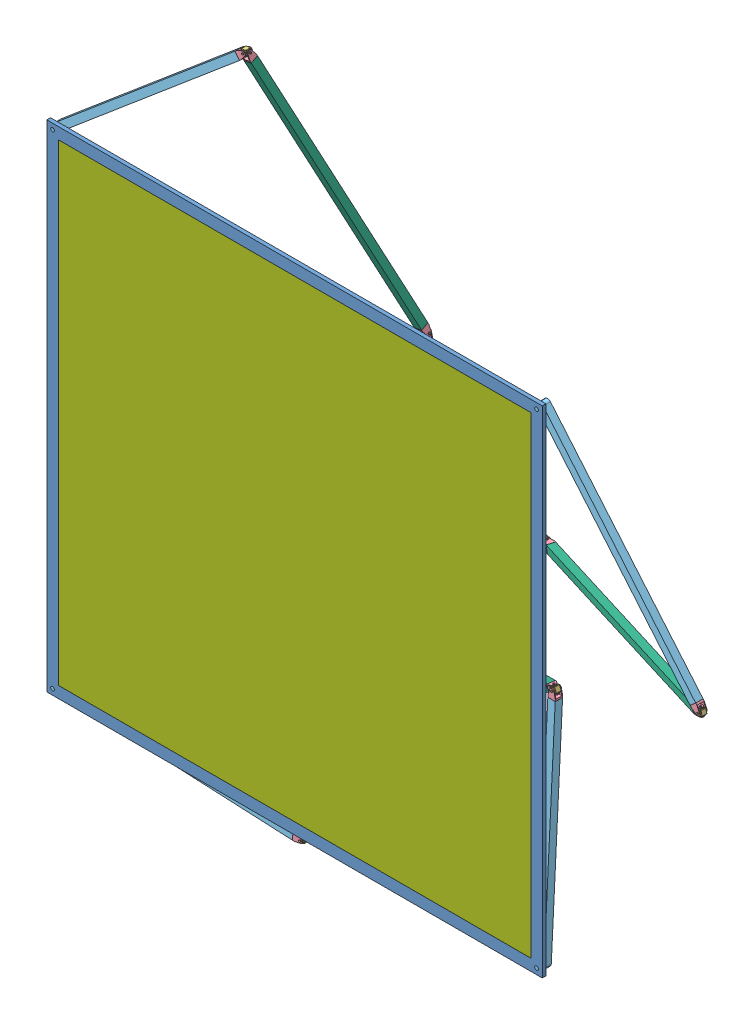
SolidWorks assembly 4ruu_assy, configuration Default. Lengths in mm.
Overall size (1795.63 1894.26 440).
49 component instances, 8 part files, 36 mates.
Components (placement in the parent):
- base_platform-1: base_platform [Default] at origin size (1343.5 1343.5 10)
- moving_platform_v2-1: moving_platform_v2 [Default] at (0 0 -355) x (0.707107 -0.707107 0) z (-0.707107 -0.707107 0) size (455.38 20 455.38)
- leg_assy-13: leg_assy [Default] at (1212.9036 -498.9058 0) x (-0.19613 0.980578 0) z (0.980578 0.19613 0) size (605.2 366.75 808.94) (flexible)
  - U_assy-1: U_assy [Default] at origin size (42.86 32.94 43.11) (flexible)
    - connector_new-2: connector_new [Default] at (661.9873 -10 0) size (23.51 23.51 14.4)
    - U_leg-3: U_leg [Default] at (661.9873 -18.0144 -18.324) x (0 0.916202 -0.400718) z (1 0 0) size (20 35.93 20)
    - U_leg-4: U_leg [Default] at (679.5062 -10 -9.6481) x (-0.482406 0 -0.875948) z (0 1 0) size (20 35.93 20)
  - active_link-2: active_link [Default] at (1241.8535 0 -319.3467) x (-0.875948 0 0.482406) z (-0.482406 0 -0.875948) size (651.99 30 20)
  - passive_link-2: passive_link [Default] at (661.9873 -18.0144 -18.324) x (0 -0.400718 -0.916202) z (0 -0.916202 0.400718) size (796 20 20)
  - U_assy-3: U_assy [Default] at (0 343.3292 -1443.6209) x (1 0 0) z (0 0 -1) size (27.44 32.94 62.87) (flexible)
    - connector_new-2: connector_new [Default] at (661.9873 688.3292 -677.6764) size (23.51 23.51 14.4)
    - U_leg-3: U_leg [Default] at (661.9873 680.3148 -696.0004) x (0 0.916202 -0.400718) z (1 0 0) size (20 35.93 20)
    - U_leg-4: U_leg [Default] at (665.9099 688.3292 -658.0648) x (0.980578 0 -0.19613) z (0 1 0) size (20 35.93 20)
- leg_assy-14: leg_assy [Default] at (360.6975 1504.003 0) x (-0.7718 -0.635865 0) z (-0.635865 0.7718 0) size (685.82 385.73 722.67) (flexible)
  - U_assy-1: U_assy [Default] at origin size (43.88 32.94 45.52) (flexible)
    - connector_new-2: connector_new [Default] at (661.9873 -10 0) x (-0.881522 0 -0.472143) z (0.472143 0 -0.881522) size (23.51 23.51 14.4)
    - U_leg-3: U_leg [Default] at (670.6388 -18.0144 -16.153) x (-0.189196 -0.916202 0.353242) z (-0.881522 0 -0.472143) size (20 35.93 20)
    - U_leg-4: U_leg [Default] at (681.9859 -10 -0.2336) x (-0.011679 0 -0.999932) z (0 1 0) size (20 35.93 20)
  - active_link-2: active_link [Default] at (1323.9294 0 -7.7317) x (-0.999932 0 0.011679) z (-0.011679 0 -0.999932) size (651.99 30 20)
  - passive_link-2: passive_link [Default] at (670.6388 -18.0144 -16.153) x (0.432578 -0.400718 -0.807652) z (0.189196 0.916202 -0.353242) size (796 20 20)
  - U_assy-3: U_assy [Default] at (426.0899 -234.6598 -958.9033) x (-0.63995 -0.687737 -0.342757) z (-0.631095 0.215924 0.745048) size (38.45 36.85 64.31) (flexible)
    - connector_new-2: connector_new [Default] at (-403.7477 500.767 -189.5501) x (0.72596 -0.656612 0.204555) z (0 0.297433 0.954743) size (23.51 23.51 14.4)
    - U_leg-3: U_leg [Default] at (-409.2595 500.6624 -170.3249) x (-0.630106 -0.75421 -0.184752) z (0.72596 -0.656612 0.204555) size (20 35.93 20)
    - U_leg-4: U_leg [Default] at (-406.5953 497.5095 -209.0765) x (-0.71186 0.702195 -0.013329) z (0.687737 0.693105 -0.215924) size (20 35.93 20)
- leg_assy-15: leg_assy [Default] at (161.0399 405.9668 0) x (0.795734 -0.605646 0) z (-0.605646 -0.795734 0) size (763.11 383.26 718.79) (flexible)
  - U_assy-1: U_assy [Default] at origin size (48.3 32.94 45.55) (flexible)
    - connector_new-2: connector_new [Default] at (661.9873 -10 0) x (-0.894006 0 -0.448056) z (0.448056 0 -0.894006) size (23.51 23.51 14.4)
    - U_leg-3: U_leg [Default] at (653.7771 -18.0144 16.3818) x (-0.179544 0.916202 0.358244) z (-0.894006 0 -0.448056) size (20 35.93 20)
    - U_leg-4: U_leg [Default] at (673.3264 -10 16.4749) x (0.823747 0 -0.566957) z (0 1 0) size (20 35.93 20)
  - active_link-2: active_link [Default] at (1037.3058 0 545.3101) x (-0.566957 0 -0.823747) z (0.823747 0 -0.566957) size (651.99 30 20)
  - passive_link-2: passive_link [Default] at (653.7771 -18.0144 16.3818) x (-0.410509 -0.400718 0.819089) z (0.179544 -0.916202 -0.358244) size (796 20 20)
  - U_assy-3: U_assy [Default] at (-194.4463 -225.0765 463.3547) x (-0.852508 0.301132 -0.427258) z (-0.347705 0.283627 0.893676) size (47.65 46 44.14) (flexible)
    - connector_new-2: connector_new [Default] at (-568.2573 -60.7851 -14.6089) x (0.953583 0.287503 -0.089566) z (0 0.297433 0.954743) size (23.51 23.51 14.4)
    - U_leg-3: U_leg [Default] at (-565.8439 -73.5318 -29.8305) x (-0.275897 0.714947 -0.642441) z (0.953583 0.287503 -0.089566) size (20 35.93 20)
    - U_leg-4: U_leg [Default] at (-551.1313 -58.2392 -24.6197) x (-0.419603 -0.393599 -0.817932) z (-0.301132 0.910426 -0.283627) size (20 35.93 20)
- leg_assy-16: leg_assy [Default] at (666.2595 -655.9937 0) x (-0.998845 -0.048056 0) z (-0.048056 0.998845 0) size (683.51 383.26 737.07) (flexible)
  - U_assy-1: U_assy [Default] at origin size (44.47 32.94 45.51) (flexible)
    - connector_new-2: connector_new [Default] at (661.9873 -10 0) x (0.918092 0 -0.396366) z (0.396366 0 0.918092) size (23.51 23.51 14.4)
    - U_leg-3: U_leg [Default] at (669.2503 -18.0144 16.8232) x (-0.158831 -0.916202 -0.367896) z (0.918092 0 -0.396366) size (20 35.93 20)
    - U_leg-4: U_leg [Default] at (681.8955 -10 1.9139) x (0.095697 0 -0.99541) z (0 1 0) size (20 35.93 20)
  - active_link-2: active_link [Default] at (1320.9364 0 63.3503) x (-0.99541 0 -0.095697) z (0.095697 0 -0.99541) size (651.99 30 20)
  - passive_link-2: passive_link [Default] at (669.2503 -18.0144 16.8232) x (0.363151 -0.400718 0.841158) z (0.158831 0.916202 0.367896) size (796 20 20)
  - U_assy-3: U_assy [Default] at (46.7437 -855.7989 1664.5874) x (0.666498 -0.687737 -0.287746) z (-0.720723 -0.693105 -0.012812) size (46.25 45.77 46.77) (flexible)
    - connector_new-2: connector_new [Default] at (537.7417 -855.7756 -1003.9481) x (0.72596 -0.204555 -0.656612) z (0 -0.954743 0.297433) size (23.51 23.51 14.4)
    - U_leg-3: U_leg [Default] at (532.2299 -875.0008 -1004.0527) x (-0.630106 0.184752 -0.75421) z (0.72596 -0.204555 -0.656612) size (20 35.93 20)
    - U_leg-4: U_leg [Default] at (524.7037 -860.5041 -989.5379) x (0.319443 -0.947354 -0.021838) z (0.687737 0.215924 0.693105) size (20 35.93 20)
- base_glass-1: base_glass [Default] at (0 0 10) x (1 0 0) z (0 1 0) size (1281.28 10 1281.28)
- stand-1: stand [Default] at (0 0 -380) x (0.707107 -0.707107 0) z (-0.707107 -0.707107 0) size (200 70 200)
- stand-2: stand [Default] at (-212.132 -212.132 -380) x (0.707107 -0.707107 0) z (-0.707107 -0.707107 0) size (200 70 200)
Mates (geometry in assembly coordinates):
- Parallel1: parallel: plane of base_platform-1 through (0 0 0) normal (0 0 -1); plane of moving_platform_v2-1 through (0 0 -335) normal (0 0 1)
- Coincident31: coincident: plane of base_platform-1 through (0 0 0) normal (0 0 -1); plane of leg_assy-13/active_link-2 through (656.1951 656.1951 0) normal (0 0 1)
- Concentric1: concentric: cylinder of base_platform-1 through (656.1951 656.1951 10) axis (0 0 -1) radius 5; cylinder of leg_assy-13/active_link-2 through (656.1951 656.1951 10) axis (0 0 -1) radius 5
- Parallel2: parallel: plane of moving_platform_v2-1 through (312 10 -335) normal (1 0 0); plane of leg_assy-13/U_assy-3/U_leg-4 through (312 0 -345) normal (-1 0 0)
- Coincident33: coincident: plane of moving_platform_v2-1 through (302 5 -340) normal (0 0 -1); plane of leg_assy-13/U_assy-3/U_leg-4 through (302 -5 -340) normal (0 0 1)
- Coincident34: coincident: plane of moving_platform_v2-1 through (302 5 -350) normal (0 -1 0); plane of leg_assy-13/U_assy-3/U_leg-4 through (302 5 -340) normal (0 1 0)
- Coincident35: coincident: plane of moving_platform_v2-1 through (312 10 -335) normal (1 0 0); plane of leg_assy-13/U_assy-3/U_leg-4 through (312 0 -345) normal (-1 0 0)
- Coincident36: coincident: plane of base_platform-1 through (0 0 0) normal (0 0 -1); plane of leg_assy-14/active_link-2 through (-656.1951 656.1951 0) normal (0 0 1)
- Concentric2: concentric: cylinder of base_platform-1 through (-656.1951 656.1951 10) axis (0 0 -1) radius 5; cylinder of leg_assy-14/active_link-2 through (-656.1951 656.1951 10) axis (0 0 -1) radius 5
- Parallel4: parallel: plane of moving_platform_v2-1 through (-10 312 -335) normal (0 1 0); plane of leg_assy-14/U_assy-3/U_leg-4 through (0 312 -345) normal (0 -1 0)
- Coincident40: coincident: plane of moving_platform_v2-1 through (-5 302 -350) normal (1 0 0); plane of leg_assy-14/U_assy-3/U_leg-4 through (-5 302 -340) normal (-1 0 0)
- Coincident41: coincident: plane of moving_platform_v2-1 through (-5 302 -340) normal (0 0 -1); plane of leg_assy-14/U_assy-3/U_leg-4 through (5 302 -340) normal (0 0 1)
- Coincident42: coincident: plane of moving_platform_v2-1 through (-10 312 -335) normal (0 1 0); plane of leg_assy-14/U_assy-3/U_leg-4 through (0 312 -345) normal (0 -1 0)
- Concentric3: concentric: cylinder of base_platform-1 through (656.1951 -656.1951 10) axis (0 0 -1) radius 5; cylinder of leg_assy-15/active_link-2 through (656.1951 -656.1951 10) axis (0 0 -1) radius 5
- Coincident43: coincident: plane of base_platform-1 through (0 0 0) normal (0 0 -1); plane of leg_assy-15/active_link-2 through (656.1951 -656.1951 0) normal (0 0 1)
- Coincident44: coincident: plane of moving_platform_v2-1 through (5 -302 -340) normal (0 0 -1); plane of leg_assy-15/U_assy-3/U_leg-4 through (-5 -302 -340) normal (0 0 1)
- Coincident45: coincident: plane of moving_platform_v2-1 through (5 -302 -350) normal (-1 0 0); plane of leg_assy-15/U_assy-3/U_leg-4 through (5 -302 -340) normal (1 0 0)
- Coincident46: coincident: plane of moving_platform_v2-1 through (10 -312 -335) normal (0 -1 0); plane of leg_assy-15/U_assy-3/U_leg-4 through (0 -312 -345) normal (0 1 0)
- Concentric4: concentric: cylinder of base_platform-1 through (-656.1951 -656.1951 10) axis (0 0 -1) radius 5; cylinder of leg_assy-16/active_link-2 through (-656.1951 -656.1951 10) axis (0 0 -1) radius 5
- Coincident47: coincident: plane of base_platform-1 through (0 0 0) normal (0 0 -1); plane of leg_assy-16/active_link-2 through (-656.1951 -656.1951 0) normal (0 0 1)
- Coincident48: coincident: plane of moving_platform_v2-1 through (-302 -5 -340) normal (0 0 -1); plane of ? through (-302 5 -340) normal (0 0 1)
- Coincident49: coincident: plane of moving_platform_v2-1 through (-302 5 -340) normal (0 -1 0); plane of ? through (-302 5 -350) normal (0 1 0)
- Coincident50: coincident: plane of moving_platform_v2-1 through (-312 -10 -335) normal (-1 0 0); plane of ? through (-312 0 -345) normal (1 0 0)
- Coincident51: coincident: line of moving_platform_v2-1 through (0 0 -356) axis (0 0 1); plane of assembly
- Angle1: planar angle = 2.356194 rad: plane of assembly through (0 0 0) normal (-0.707107 -0.707107 0); plane of moving_platform_v2-1 through (20 -10 -335) normal (0 -1 0)
- Distance1: distance = 35 mm: plane of assembly through (0 0 -300) normal (0 0 -1); plane of moving_platform_v2-1 through (0 0 -335) normal (0 0 1)
- Distance2: distance = 0 mm: line of moving_platform_v2-1 through (0 0 -356) axis (0 0 1); plane of assembly
- Coincident53: coincident: plane of base_platform-1 through (640.6387 -640.6387 10) normal (-1 0 0); plane of base_glass-1 through (640.6387 640.6387 0) normal (1 0 0)
- Coincident54: coincident: plane of base_platform-1 through (640.6387 640.6387 10) normal (0 -1 0); plane of base_glass-1 through (-640.6387 640.6387 0) normal (0 1 0)
- Coincident55: coincident: plane of base_platform-1 through (0 0 10) normal (0 0 1); plane of base_glass-1 through (0 0 10) normal (0 0 1)
- Coincident56: coincident: plane of stand-1 through (0 0 -360) normal (0 0 1); plane of assembly through (0 0 -360) normal (0 0 -1)
- Coincident57: coincident: plane of stand-1 through (0 0 -380) normal (-0.707107 -0.707107 0); plane of assembly through (0 0 0) normal (-0.707107 -0.707107 0)
- Coincident58: coincident: plane of stand-1; plane of assembly through (0 0 0) normal (0.707107 -0.707107 0)
- Coincident59: coincident: plane of stand-2 through (-212.132 -212.132 -360) normal (0 0 1); plane of assembly through (0 0 -360) normal (0 0 -1)
- Coincident60: coincident: plane of stand-2 through (-212.132 -212.132 -380) normal (-0.707107 -0.707107 0); plane of assembly through (-212.132 -212.132 0) normal (-0.707107 -0.707107 0)
- Coincident61: coincident: plane of stand-2; plane of assembly through (0 0 0) normal (0.707107 -0.707107 0)
